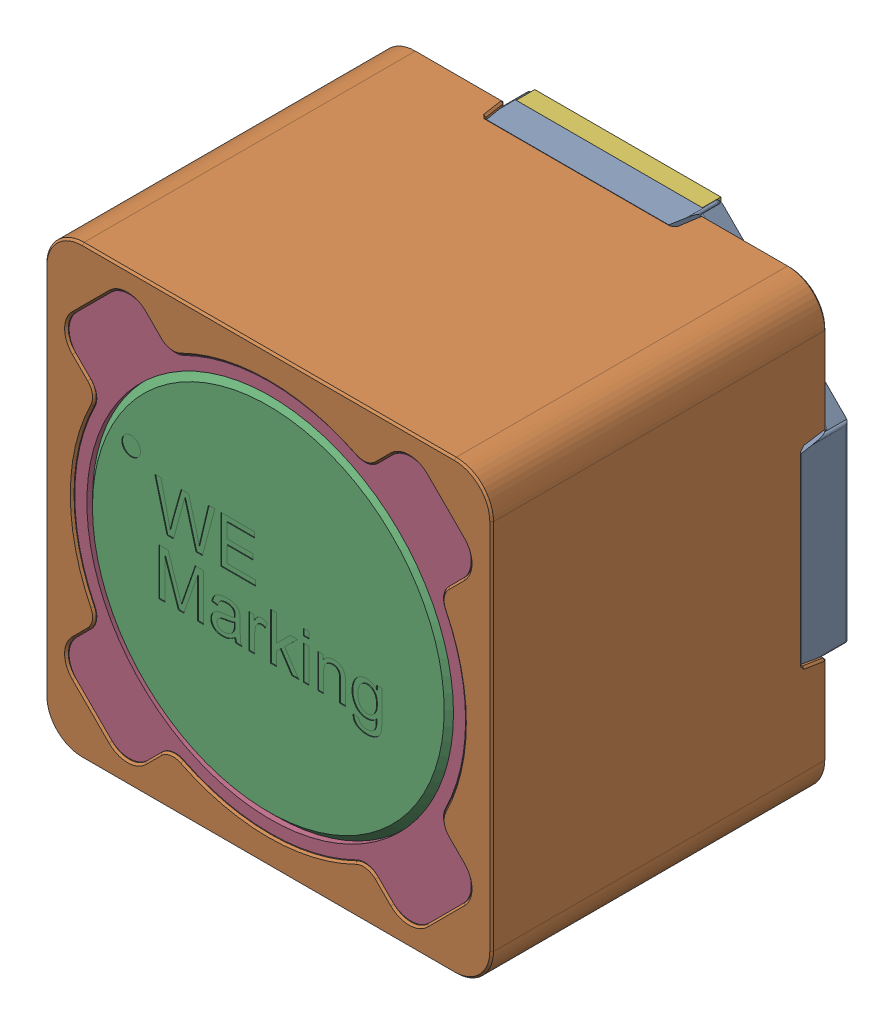
SolidWorks assembly L1, configuration Default. Lengths in mm.
Overall size (12 12 9.66).
12 component instances, 10 part files, 0 mates.
Components (placement in the parent):
- IndPDA_1210-1: IndPDA_1210 [Default] at (22.5299 16.4001 0.45) x (1 0 0) z (0 0 1) size (12 12 9.66)
  - Umspritzung12-12_1-1: Umspritzung12-12_1 [Default] at (0 0 0.94) x (1 0 0) z (0 0 -1) size (12 12 1.3)
  - 12x12-9mm-1: 12x12-9mm [Default] at (0 0 9.25) size (12 12 9)
  - Core_PD_12x12-9-1: Core_PD_12x12-9 [Default] at (0 0 4.75) size (9.85 9.85 9)
  - Glue-1: Glue [Default] at origin size (10.8 10.8 8.9)
  - Leadframe_bended-1: Leadframe_bended [Default] at origin size (11.55 12 3.98)
    - Leadframe-1: Leadframe [Default] at origin size (9.3 3.5 0.71)
    - Leadframe_2-1: Leadframe_2 [Default] at origin size (9.3 3.5 0.71)
    - PIN_1-1: PIN_1 [Default] at (-4.2957 4.2957 -5.8993) x (0.5 0.5 -0.707107) z (0.707107 -0.707107 0) size (2.61 2.72 1.6)
    - PIN_2-1: PIN_2 [Default] at (4.2957 4.2957 -5.8993) x (0.5 -0.5 0.707107) z (-0.707107 -0.707107 0) size (2.71 2.61 1.51)
    - PIN_3-1: PIN_3 [Default] at (4.2957 -4.2957 -5.8993) x (0.5 0.5 0.707107) z (-0.707107 0.707107 0) size (2.72 2.61 1.6)
    - PIN_4-1: PIN_4 [Default] at (-4.2957 -4.2957 -5.8993) x (0.5 -0.5 -0.707107) z (0.707107 0.707107 0) size (2.61 2.72 1.6)
